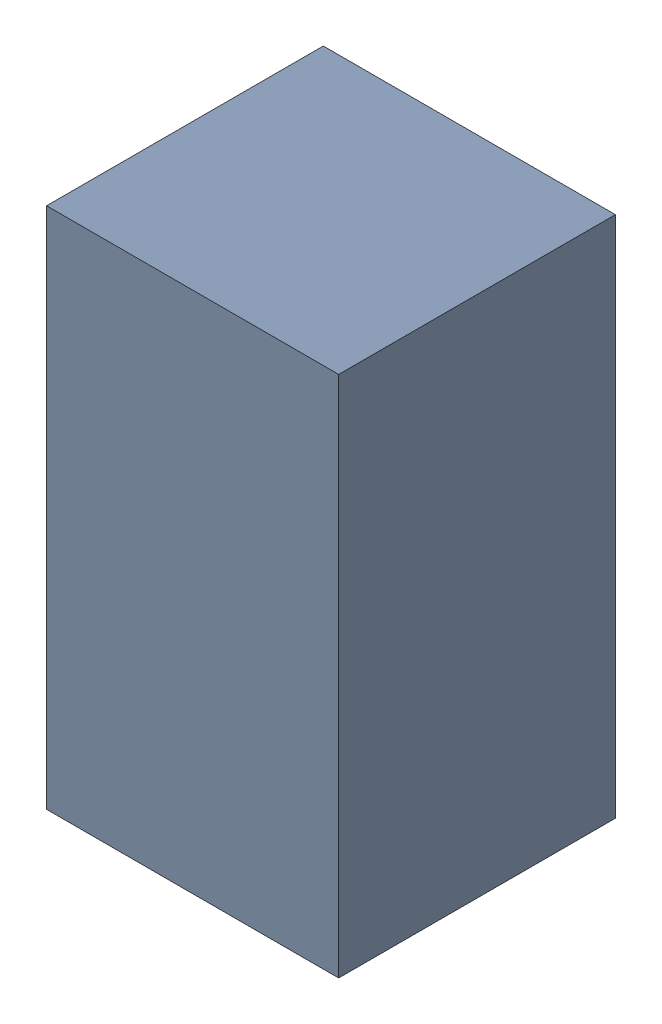
SolidWorks assembly R2, configuration Default. Lengths in mm.
Overall size (0.95 1.7 0.9).
2 component instances, 1 part files, 0 mates.
Components (placement in the parent):
- 4438511040-1: 4438511040 [Default] at (17.526 10.656 0) size (0.95 1.7 0.9)
  - Extruded_2-1: Extruded_2 [Default] at origin size (0.95 1.7 0.9)
